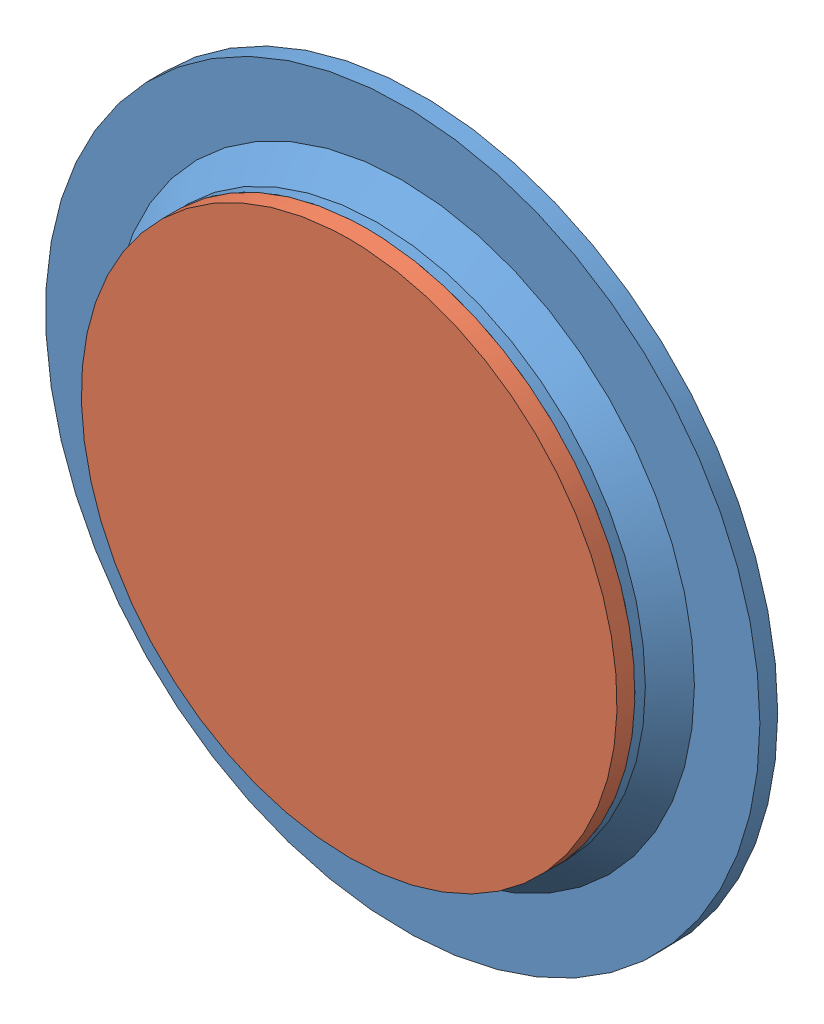
SolidWorks assembly Assem1, configuration Default. Lengths in mm.
Overall size (4 4 0.4).
2 component instances, 2 part files, 2 mates.
Components (placement in the parent):
- spacer_3mm_03height-1: spacer_3mm_03height [Default] at origin size (4 4 0.3)
- nr0_3mm_cover_slip-1: nr0_3mm_cover_slip [Default] at (0 0 0.1) x (1 0 0) z (0 1 0) size (3 0.1 3)
Mates (geometry in assembly coordinates):
- Coincident2: coincident: plane of spacer_3mm_03height-1 through (1.5 0 0) normal (0 0 1); plane of nr0_3mm_cover_slip-1 through (0 0 0) normal (0 0 -1)
- Coincident3: coincident: circle of spacer_3mm_03height-1; circle of nr0_3mm_cover_slip-1
